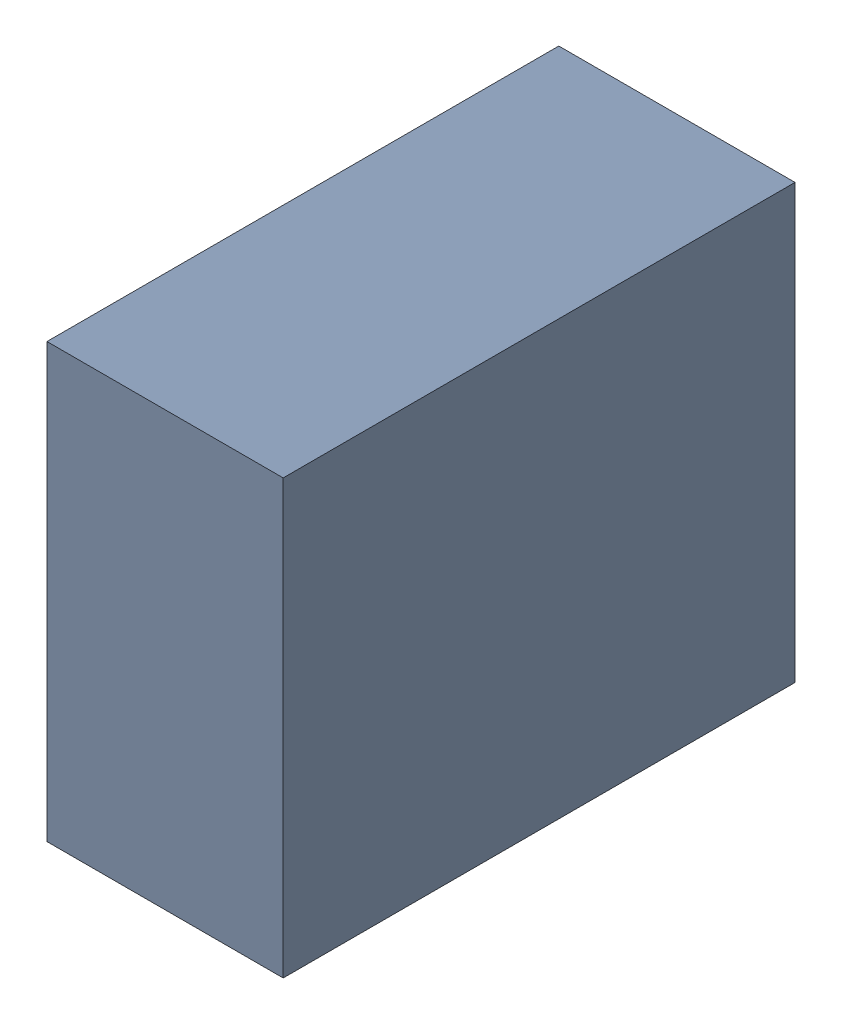
SolidWorks assembly C201, configuration Standard. Lengths in mm.
Overall size (0.6 1.1 1.3).
2 component instances, 1 part files, 0 mates.
Components (placement in the parent):
- 885542376-1: 885542376 [Standard] at (15.65 -22.65 0) size (0.6 1.1 1.3)
  - Extruded_25-1: Extruded_25 [Standard] at origin size (0.6 1.1 1.3)
